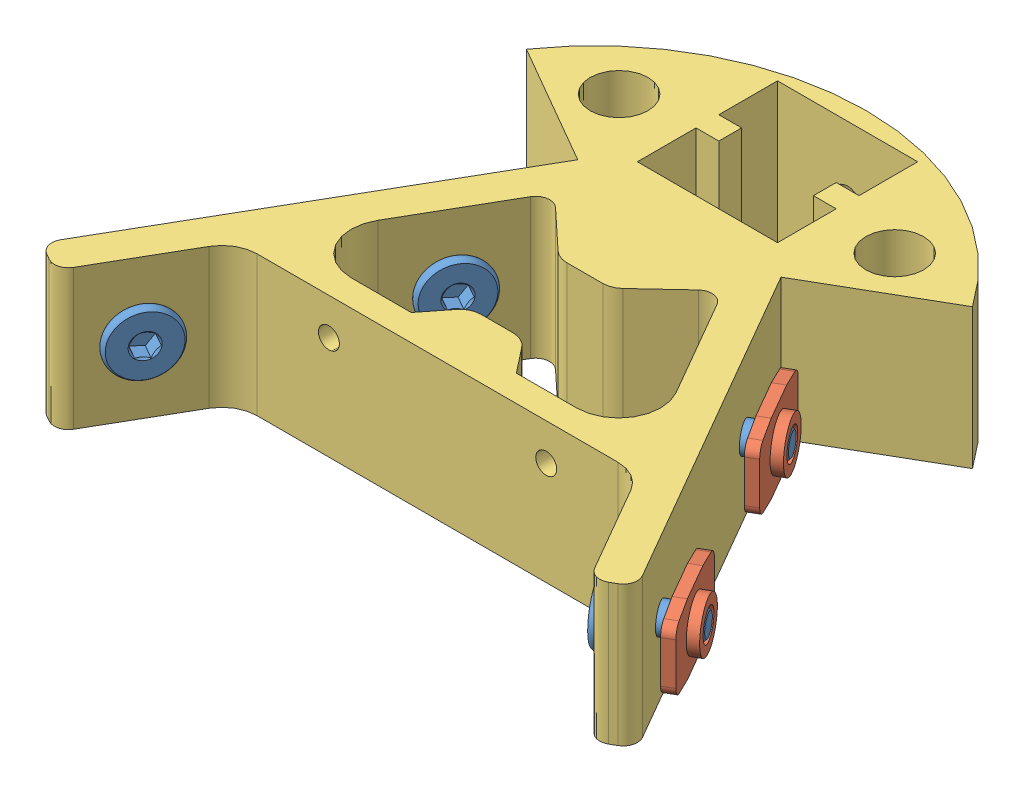
SolidWorks assembly Lower Vertex, configuration Default. Lengths in mm.
Overall size (95.45 20.12 77.45).
13 component instances, 3 part files, 4 mates.
Components (placement in the parent):
- M4 Screw with T-nut-1: M4 Screw with T-nut [Default] at (43.8034 62.231 37.8462) x (-0.866025 0 -0.5) z (-0.466142 -0.361725 0.807382) size (11.5 14.75 17.6)
  - Low Profile Screw M4-1: Low Profile Screw M4 [M5 x 8] at (1.8539 1.5522 0.4737) size (11.5 9 9)
  - Tee Nut M4-1: Tee Nut M4 [Default] at (-1.1461 1.5522 0.4737) x (0 0.361725 -0.932285) z (1 0 0) size (15 10 3)
- M4 Screw with T-nut-2: M4 Screw with T-nut [Default] at (108.954 58.9942 66.1404) x (0.866025 0 -0.5) z (0.466142 0.361725 0.807382) size (11.5 14.75 17.6)
  - Low Profile Screw M4-1: Low Profile Screw M4 [M5 x 8] at (1.8539 1.5522 0.4737) size (11.5 9 9)
  - Tee Nut M4-1: Tee Nut M4 [Default] at (-1.1461 1.5522 0.4737) x (0 0.361725 -0.932285) z (1 0 0) size (15 10 3)
- M4 Screw with T-nut-4: M4 Screw with T-nut [Default] at (92.6183 58.9942 37.8462) x (0.866025 0 -0.5) z (0.466142 0.361725 0.807382) size (11.5 14.75 17.6)
  - Low Profile Screw M4-1: Low Profile Screw M4 [M5 x 8] at (1.8539 1.5522 0.4737) size (11.5 9 9)
  - Tee Nut M4-1: Tee Nut M4 [Default] at (-1.1461 1.5522 0.4737) x (0 0.361725 -0.932285) z (1 0 0) size (15 10 3)
- M4 Screw with T-nut-5: M4 Screw with T-nut [Default] at (27.4678 62.231 66.1404) x (-0.866025 0 -0.5) z (-0.466142 -0.361725 0.807382) size (11.5 14.75 17.6)
  - Low Profile Screw M4-1: Low Profile Screw M4 [M5 x 8] at (1.8539 1.5522 0.4737) size (11.5 9 9)
  - Tee Nut M4-1: Tee Nut M4 [Default] at (-1.1461 1.5522 0.4737) x (0 0.361725 -0.932285) z (1 0 0) size (15 10 3)
- Vertex-6: Vertex [Lower Vertex] at (68.2109 50.6126 50.9383) size (83.54 20 76.93)
Mates (geometry in assembly coordinates):
- Coincident21: coincident aligned: circle of M4 Screw with T-nut-1/Low Profile Screw M4-1; circle of Vertex-6
- Coincident23: coincident aligned: circle of M4 Screw with T-nut-5/Low Profile Screw M4-1; circle of Vertex-6
- Coincident25: coincident aligned: circle of M4 Screw with T-nut-2/Low Profile Screw M4-1; circle of Vertex-6
- Coincident26: coincident aligned: circle of M4 Screw with T-nut-4/Low Profile Screw M4-1; circle of Vertex-6
